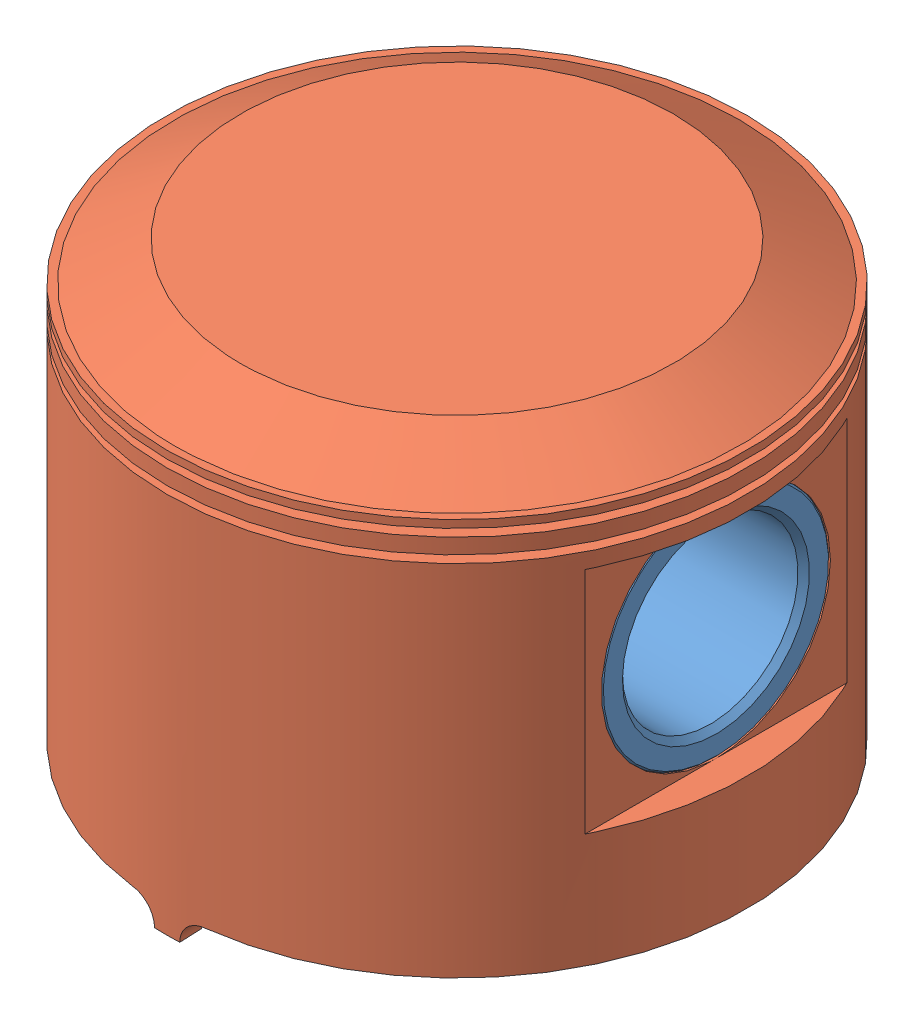
SolidWorks assembly ASSY, configuration Default. Lengths in mm.
Overall size (76 60.17 76).
2 component instances, 2 part files, 2 mates.
Components (placement in the parent):
- gudgeon-1: gudgeon [Default] at (50.7834 29.362 5.3547) x (0 0.790086 0.612996) z (1 0 0) size (30 30 67.81)
- piston v2-1: piston v2 [Third Instance] at (84.6764 56.362 5.3547) size (76 60.17 76)
Mates (geometry in assembly coordinates):
- Concentric2: concentric anti-aligned: cylinder of gudgeon-1 through (118.5906 29.362 5.3547) axis (-1 0 0) radius 15; cylinder of piston v2-1 through (46.6764 29.362 5.3547) axis (1 0 0) radius 15
- Coincident2: coincident aligned: plane of gudgeon-1 through (118.5906 29.362 5.3547) normal (1 0 0); plane of piston v2-1 through (118.5906 44.362 -32.6453) normal (1 0 0)
